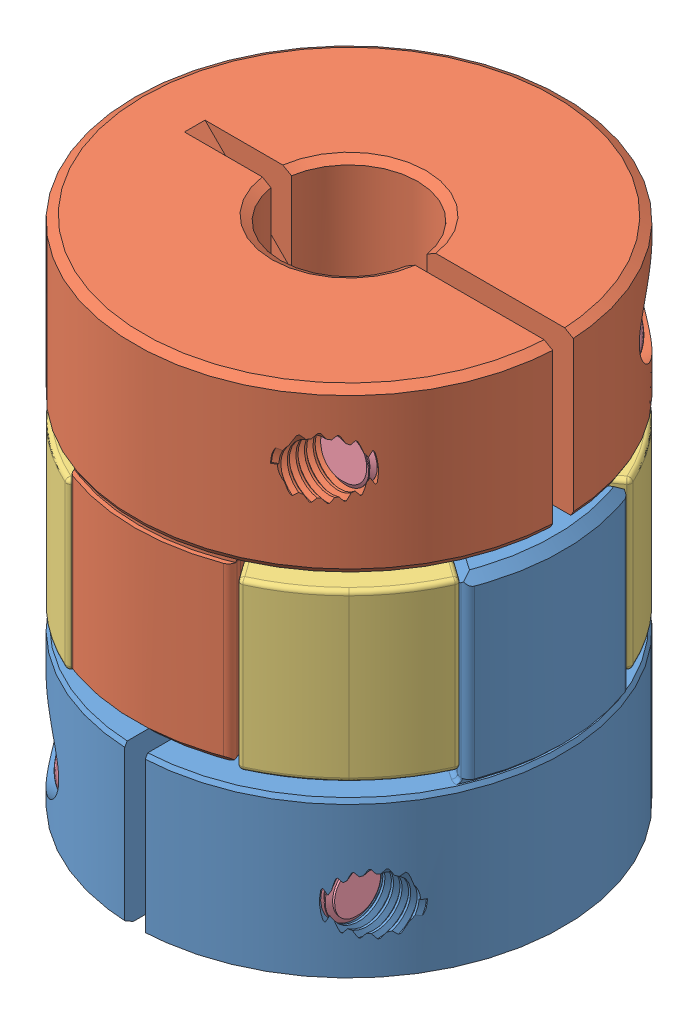
SolidWorks assembly L30xD25 CouplerASM 8to8, configuration Default. Lengths in mm.
Overall size (35.36 30 35.36).
5 component instances, 4 part files, 0 mates.
Components (placement in the parent):
- Coupler_A-1: Coupler_A [Coupler_A] at origin size (25 19.8 24.99)
- Coupler_B-1: Coupler_B [Coupler_B] at (0 30 0) x (0 0 1) z (1 0 0) size (25 19.8 24.99)
- Dampener-1: Dampener [Dampener] at (0 15 0) x (0.707107 0 -0.707107) z (0.707107 0 0.707107) size (25 11.4 25)
- M3x12_Screw-1: M3x12_Screw [M3x12_Screw] at (8 26 -6.6) x (-0.864121 -0.503284 0) z (0.503284 -0.864121 0) size (5.5 15 5.5)
- M3x12_Screw-2: M3x12_Screw [M3x12_Screw] at (-6.6 4 8) x (0 -0.393038 0.919522) z (0 -0.919522 -0.393038) size (5.5 15 5.5)
